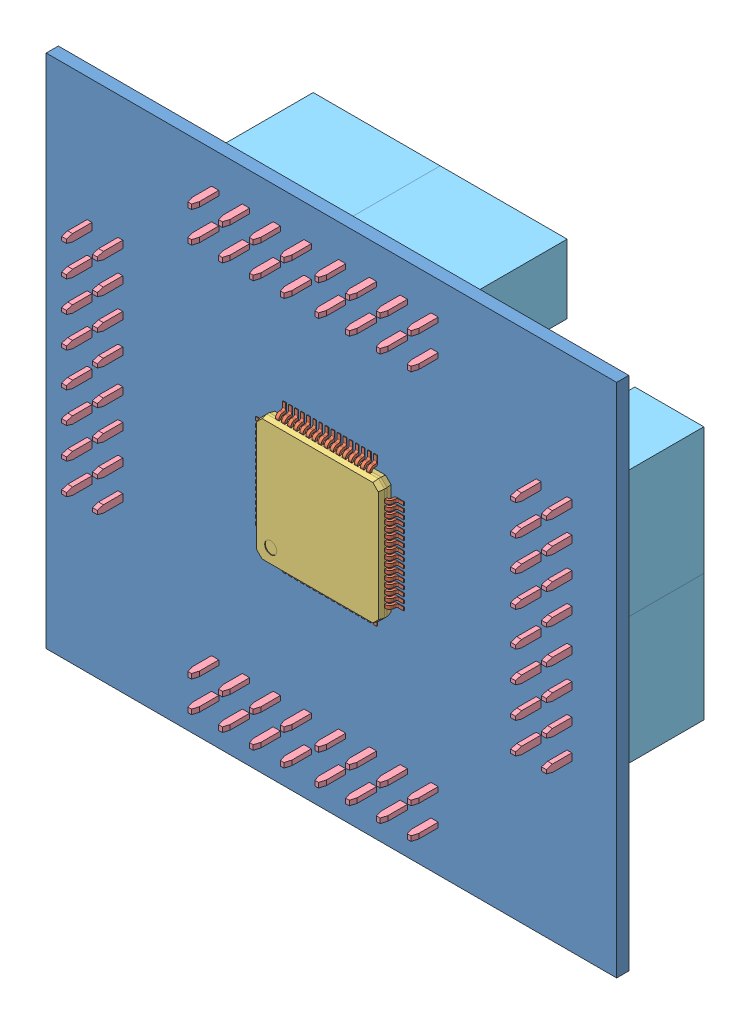
SolidWorks assembly Pic32Board, configuration Défaut. Lengths in mm.
Overall size (47 42.5 11.6).
151 component instances, 5 part files, 10 mates.
Components (placement in the parent):
- Pic32Board-1: Pic32Board [Défaut] at (-29.7416 -22.193 46.5) size (47 42.5 1)
- User Library-TQFP64-2-1: User Library-TQFP64-2 [Default] at (-6.3416 -0.843 48.025) x (1 0 0) z (0 -1 0) size (12.2 1.2 12.2)
  - User Library-TQFP64-2_Leg x0-27 y0-575 z1-0-1: User Library-TQFP64-2_Leg x0-27 y0-575 z1-0 [Default] at (-5.1 0 -1.25) x (0 0 1) z (-1 0 0) size (0.27 0.78 1)
  - User Library-TQFP64-2_Leg x0-27 y0-575 z1-0-2: User Library-TQFP64-2_Leg x0-27 y0-575 z1-0 [Default] at (-2.75 0 -5.1001) x (-1 0 0) z (0 0 -1) size (0.27 0.78 1)
  - User Library-TQFP64-2_Leg x0-27 y0-575 z1-0-3: User Library-TQFP64-2_Leg x0-27 y0-575 z1-0 [Default] at (-5.1 0 2.25) x (0 0 1) z (-1 0 0) size (0.27 0.78 1)
  - User Library-TQFP64-2_Leg x0-27 y0-575 z1-0-4: User Library-TQFP64-2_Leg x0-27 y0-575 z1-0 [Default] at (5.1 0 -3.25) x (0 0 -1) z (1 0 0) size (0.27 0.78 1)
  - User Library-TQFP64-2_Leg x0-27 y0-575 z1-0-5: User Library-TQFP64-2_Leg x0-27 y0-575 z1-0 [Default] at (-1.25 0 5.1001) size (0.27 0.78 1)
  - User Library-TQFP64-2_Leg x0-27 y0-575 z1-0-6: User Library-TQFP64-2_Leg x0-27 y0-575 z1-0 [Default] at (2.75 0 5.1001) size (0.27 0.78 1)
  - User Library-TQFP64-2_Leg x0-27 y0-575 z1-0-7: User Library-TQFP64-2_Leg x0-27 y0-575 z1-0 [Default] at (2.25 0 5.1001) size (0.27 0.78 1)
  - User Library-TQFP64-2_Leg x0-27 y0-575 z1-0-8: User Library-TQFP64-2_Leg x0-27 y0-575 z1-0 [Default] at (5.1 0 -0.25) x (0 0 -1) z (1 0 0) size (0.27 0.78 1)
  - User Library-TQFP64-2_Leg x0-27 y0-575 z1-0-9: User Library-TQFP64-2_Leg x0-27 y0-575 z1-0 [Default] at (-5.1 0 -0.75) x (0 0 1) z (-1 0 0) size (0.27 0.78 1)
  - User Library-TQFP64-2_Leg x0-27 y0-575 z1-0-10: User Library-TQFP64-2_Leg x0-27 y0-575 z1-0 [Default] at (2.25 0 -5.1001) x (-1 0 0) z (0 0 -1) size (0.27 0.78 1)
  - User Library-TQFP64-2_Leg x0-27 y0-575 z1-0-11: User Library-TQFP64-2_Leg x0-27 y0-575 z1-0 [Default] at (5.1 0 0.75) x (0 0 -1) z (1 0 0) size (0.27 0.78 1)
  - User Library-TQFP64-2_Leg x0-27 y0-575 z1-0-12: User Library-TQFP64-2_Leg x0-27 y0-575 z1-0 [Default] at (-0.25 0 -5.1001) x (-1 0 0) z (0 0 -1) size (0.27 0.78 1)
  - User Library-TQFP64-2_Leg x0-27 y0-575 z1-0-13: User Library-TQFP64-2_Leg x0-27 y0-575 z1-0 [Default] at (5.1 0 0.25) x (0 0 -1) z (1 0 0) size (0.27 0.78 1)
  - User Library-TQFP64-2_Leg x0-27 y0-575 z1-0-14: User Library-TQFP64-2_Leg x0-27 y0-575 z1-0 [Default] at (1.75 0 5.1001) size (0.27 0.78 1)
  - User Library-TQFP64-2_Leg x0-27 y0-575 z1-0-15: User Library-TQFP64-2_Leg x0-27 y0-575 z1-0 [Default] at (-1.25 0 -5.1001) x (-1 0 0) z (0 0 -1) size (0.27 0.78 1)
  - User Library-TQFP64-2_Leg x0-27 y0-575 z1-0-16: User Library-TQFP64-2_Leg x0-27 y0-575 z1-0 [Default] at (-5.1 0 1.75) x (0 0 1) z (-1 0 0) size (0.27 0.78 1)
  - User Library-TQFP64-2_Leg x0-27 y0-575 z1-0-17: User Library-TQFP64-2_Leg x0-27 y0-575 z1-0 [Default] at (3.25 0 5.1001) size (0.27 0.78 1)
  - User Library-TQFP64-2_Leg x0-27 y0-575 z1-0-18: User Library-TQFP64-2_Leg x0-27 y0-575 z1-0 [Default] at (2.75 0 -5.1001) x (-1 0 0) z (0 0 -1) size (0.27 0.78 1)
  - User Library-TQFP64-2_Leg x0-27 y0-575 z1-0-19: User Library-TQFP64-2_Leg x0-27 y0-575 z1-0 [Default] at (5.1 0 2.25) x (0 0 -1) z (1 0 0) size (0.27 0.78 1)
  - User Library-TQFP64-2_Leg x0-27 y0-575 z1-0-20: User Library-TQFP64-2_Leg x0-27 y0-575 z1-0 [Default] at (-3.25 0 -5.1001) x (-1 0 0) z (0 0 -1) size (0.27 0.78 1)
  - User Library-TQFP64-2_Leg x0-27 y0-575 z1-0-21: User Library-TQFP64-2_Leg x0-27 y0-575 z1-0 [Default] at (-3.75 0 5.1001) size (0.27 0.78 1)
  - User Library-TQFP64-2_Leg x0-27 y0-575 z1-0-22: User Library-TQFP64-2_Leg x0-27 y0-575 z1-0 [Default] at (-3.25 0 5.1001) size (0.27 0.78 1)
  - User Library-TQFP64-2_Leg x0-27 y0-575 z1-0-23: User Library-TQFP64-2_Leg x0-27 y0-575 z1-0 [Default] at (3.75 0 5.1001) size (0.27 0.78 1)
  - User Library-TQFP64-2_Leg x0-27 y0-575 z1-0-24: User Library-TQFP64-2_Leg x0-27 y0-575 z1-0 [Default] at (-5.1 0 0.25) x (0 0 1) z (-1 0 0) size (0.27 0.78 1)
  - User Library-TQFP64-2_Leg x0-27 y0-575 z1-0-25: User Library-TQFP64-2_Leg x0-27 y0-575 z1-0 [Default] at (5.1 0 3.25) x (0 0 -1) z (1 0 0) size (0.27 0.78 1)
  - User Library-TQFP64-2_Leg x0-27 y0-575 z1-0-26: User Library-TQFP64-2_Leg x0-27 y0-575 z1-0 [Default] at (-5.1 0 0.75) x (0 0 1) z (-1 0 0) size (0.27 0.78 1)
  - User Library-TQFP64-2_Leg x0-27 y0-575 z1-0-27: User Library-TQFP64-2_Leg x0-27 y0-575 z1-0 [Default] at (0.75 0 -5.1001) x (-1 0 0) z (0 0 -1) size (0.27 0.78 1)
  - User Library-TQFP64-2_Leg x0-27 y0-575 z1-0-28: User Library-TQFP64-2_Leg x0-27 y0-575 z1-0 [Default] at (5.1 0 1.75) x (0 0 -1) z (1 0 0) size (0.27 0.78 1)
  - User Library-TQFP64-2_Leg x0-27 y0-575 z1-0-29: User Library-TQFP64-2_Leg x0-27 y0-575 z1-0 [Default] at (-5.1 0 -3.75) x (0 0 1) z (-1 0 0) size (0.27 0.78 1)
  - User Library-TQFP64-2_Leg x0-27 y0-575 z1-0-30: User Library-TQFP64-2_Leg x0-27 y0-575 z1-0 [Default] at (5.1 0 -0.75) x (0 0 -1) z (1 0 0) size (0.27 0.78 1)
  - User Library-TQFP64-2_Leg x0-27 y0-575 z1-0-31: User Library-TQFP64-2_Leg x0-27 y0-575 z1-0 [Default] at (5.1 0 3.75) x (0 0 -1) z (1 0 0) size (0.27 0.78 1)
  - User Library-TQFP64-2_Leg x0-27 y0-575 z1-0-32: User Library-TQFP64-2_Leg x0-27 y0-575 z1-0 [Default] at (-2.25 0 5.1001) size (0.27 0.78 1)
  - User Library-TQFP64-2_Leg x0-27 y0-575 z1-0-33: User Library-TQFP64-2_Leg x0-27 y0-575 z1-0 [Default] at (-5.1 0 -3.25) x (0 0 1) z (-1 0 0) size (0.27 0.78 1)
  - User Library-TQFP64-2_Leg x0-27 y0-575 z1-0-34: User Library-TQFP64-2_Leg x0-27 y0-575 z1-0 [Default] at (-5.1 0 2.75) x (0 0 1) z (-1 0 0) size (0.27 0.78 1)
  - User Library-TQFP64-2_Leg x0-27 y0-575 z1-0-35: User Library-TQFP64-2_Leg x0-27 y0-575 z1-0 [Default] at (-5.1 0 3.75) x (0 0 1) z (-1 0 0) size (0.27 0.78 1)
  - User Library-TQFP64-2_Leg x0-27 y0-575 z1-0-36: User Library-TQFP64-2_Leg x0-27 y0-575 z1-0 [Default] at (1.25 0 -5.1001) x (-1 0 0) z (0 0 -1) size (0.27 0.78 1)
  - User Library-TQFP64-2_Leg x0-27 y0-575 z1-0-37: User Library-TQFP64-2_Leg x0-27 y0-575 z1-0 [Default] at (1.25 0 5.1001) size (0.27 0.78 1)
  - User Library-TQFP64-2_Leg x0-27 y0-575 z1-0-38: User Library-TQFP64-2_Leg x0-27 y0-575 z1-0 [Default] at (5.1 0 1.25) x (0 0 -1) z (1 0 0) size (0.27 0.78 1)
  - User Library-TQFP64-2_Leg x0-27 y0-575 z1-0-39: User Library-TQFP64-2_Leg x0-27 y0-575 z1-0 [Default] at (0.75 0 5.1001) size (0.27 0.78 1)
  - User Library-TQFP64-2_Leg x0-27 y0-575 z1-0-40: User Library-TQFP64-2_Leg x0-27 y0-575 z1-0 [Default] at (3.25 0 -5.1001) x (-1 0 0) z (0 0 -1) size (0.27 0.78 1)
  - User Library-TQFP64-2_Leg x0-27 y0-575 z1-0-41: User Library-TQFP64-2_Leg x0-27 y0-575 z1-0 [Default] at (-2.75 0 5.1001) size (0.27 0.78 1)
  - User Library-TQFP64-2_Leg x0-27 y0-575 z1-0-42: User Library-TQFP64-2_Leg x0-27 y0-575 z1-0 [Default] at (3.75 0 -5.1001) x (-1 0 0) z (0 0 -1) size (0.27 0.78 1)
  - User Library-TQFP64-2_Leg x0-27 y0-575 z1-0-43: User Library-TQFP64-2_Leg x0-27 y0-575 z1-0 [Default] at (1.75 0 -5.1001) x (-1 0 0) z (0 0 -1) size (0.27 0.78 1)
  - User Library-TQFP64-2_Leg x0-27 y0-575 z1-0-44: User Library-TQFP64-2_Leg x0-27 y0-575 z1-0 [Default] at (-5.1 0 -2.75) x (0 0 1) z (-1 0 0) size (0.27 0.78 1)
  - User Library-TQFP64-2_Leg x0-27 y0-575 z1-0-45: User Library-TQFP64-2_Leg x0-27 y0-575 z1-0 [Default] at (5.1 0 -2.25) x (0 0 -1) z (1 0 0) size (0.27 0.78 1)
  - User Library-TQFP64-2_Leg x0-27 y0-575 z1-0-46: User Library-TQFP64-2_Leg x0-27 y0-575 z1-0 [Default] at (-2.25 0 -5.1001) x (-1 0 0) z (0 0 -1) size (0.27 0.78 1)
  - User Library-TQFP64-2_Leg x0-27 y0-575 z1-0-47: User Library-TQFP64-2_Leg x0-27 y0-575 z1-0 [Default] at (-5.1 0 1.25) x (0 0 1) z (-1 0 0) size (0.27 0.78 1)
  - User Library-TQFP64-2_Leg x0-27 y0-575 z1-0-48: User Library-TQFP64-2_Leg x0-27 y0-575 z1-0 [Default] at (5.1 0 -3.75) x (0 0 -1) z (1 0 0) size (0.27 0.78 1)
  - User Library-TQFP64-2_Leg x0-27 y0-575 z1-0-49: User Library-TQFP64-2_Leg x0-27 y0-575 z1-0 [Default] at (0.25 0 -5.1001) x (-1 0 0) z (0 0 -1) size (0.27 0.78 1)
  - User Library-TQFP64-2_Leg x0-27 y0-575 z1-0-50: User Library-TQFP64-2_Leg x0-27 y0-575 z1-0 [Default] at (-3.75 0 -5.1001) x (-1 0 0) z (0 0 -1) size (0.27 0.78 1)
  - User Library-TQFP64-2_Leg x0-27 y0-575 z1-0-51: User Library-TQFP64-2_Leg x0-27 y0-575 z1-0 [Default] at (-5.1 0 -0.25) x (0 0 1) z (-1 0 0) size (0.27 0.78 1)
  - User Library-TQFP64-2_Leg x0-27 y0-575 z1-0-52: User Library-TQFP64-2_Leg x0-27 y0-575 z1-0 [Default] at (-0.75 0 5.1001) size (0.27 0.78 1)
  - User Library-TQFP64-2_Leg x0-27 y0-575 z1-0-53: User Library-TQFP64-2_Leg x0-27 y0-575 z1-0 [Default] at (5.1 0 -1.75) x (0 0 -1) z (1 0 0) size (0.27 0.78 1)
  - User Library-TQFP64-2_Leg x0-27 y0-575 z1-0-54: User Library-TQFP64-2_Leg x0-27 y0-575 z1-0 [Default] at (-5.1 0 -2.25) x (0 0 1) z (-1 0 0) size (0.27 0.78 1)
  - User Library-TQFP64-2_Leg x0-27 y0-575 z1-0-55: User Library-TQFP64-2_Leg x0-27 y0-575 z1-0 [Default] at (-0.75 0 -5.1001) x (-1 0 0) z (0 0 -1) size (0.27 0.78 1)
  - User Library-TQFP64-2_Leg x0-27 y0-575 z1-0-56: User Library-TQFP64-2_Leg x0-27 y0-575 z1-0 [Default] at (-5.1 0 3.25) x (0 0 1) z (-1 0 0) size (0.27 0.78 1)
  - User Library-TQFP64-2_Body x10-2 y10-2 z1-05-1: User Library-TQFP64-2_Body x10-2 y10-2 z1-05 [Default] at origin size (10.2 1.05 10.2)
  - User Library-TQFP64-2_Leg x0-27 y0-575 z1-0-57: User Library-TQFP64-2_Leg x0-27 y0-575 z1-0 [Default] at (0.25 0 5.1001) size (0.27 0.78 1)
  - User Library-TQFP64-2_Leg x0-27 y0-575 z1-0-58: User Library-TQFP64-2_Leg x0-27 y0-575 z1-0 [Default] at (5.1 0 2.75) x (0 0 -1) z (1 0 0) size (0.27 0.78 1)
  - User Library-TQFP64-2_Leg x0-27 y0-575 z1-0-59: User Library-TQFP64-2_Leg x0-27 y0-575 z1-0 [Default] at (-1.75 0 -5.1001) x (-1 0 0) z (0 0 -1) size (0.27 0.78 1)
  - User Library-TQFP64-2_Leg x0-27 y0-575 z1-0-60: User Library-TQFP64-2_Leg x0-27 y0-575 z1-0 [Default] at (-5.1 0 -1.75) x (0 0 1) z (-1 0 0) size (0.27 0.78 1)
  - User Library-TQFP64-2_Leg x0-27 y0-575 z1-0-61: User Library-TQFP64-2_Leg x0-27 y0-575 z1-0 [Default] at (-0.25 0 5.1001) size (0.27 0.78 1)
  - User Library-TQFP64-2_Leg x0-27 y0-575 z1-0-62: User Library-TQFP64-2_Leg x0-27 y0-575 z1-0 [Default] at (-1.75 0 5.1001) size (0.27 0.78 1)
  - User Library-TQFP64-2_Leg x0-27 y0-575 z1-0-63: User Library-TQFP64-2_Leg x0-27 y0-575 z1-0 [Default] at (5.1 0 -2.75) x (0 0 -1) z (1 0 0) size (0.27 0.78 1)
  - User Library-TQFP64-2_Leg x0-27 y0-575 z1-0-64: User Library-TQFP64-2_Leg x0-27 y0-575 z1-0 [Default] at (5.1 0 -1.25) x (0 0 -1) z (1 0 0) size (0.27 0.78 1)
- HE10-16Way-Female-1: HE10-16Way-Female [Défaut] at (-8.4334 -17.4128 55.4002) x (1 0 0) z (0 0 -1) size (20.92 5.68 11.6)
  - User Library-MULTICOMP 2214S-08SG-85-1: User Library-MULTICOMP 2214S-08SG-85 [Default] at (-3.5782 -0.0598 8.9002) size (10.46 5.68 11.6)
    - User Library-MULTICOMP 2214S-08SG-85_contact-1: User Library-MULTICOMP 2214S-08SG-85_contact [Default] at (-3.81 -1.07 0.9) x (1 0 0) z (0 -1 0) size (2 10 0.4)
    - User Library-MULTICOMP 2214S-08SG-85_contact-2: User Library-MULTICOMP 2214S-08SG-85_contact [Default] at (-3.81 1.47 0.9) x (1 0 0) z (0 -1 0) size (2 10 0.4)
    - User Library-MULTICOMP 2214S-08SG-85_contact-3: User Library-MULTICOMP 2214S-08SG-85_contact [Default] at (-1.27 -1.07 0.9) x (1 0 0) z (0 -1 0) size (2 10 0.4)
    - User Library-MULTICOMP 2214S-08SG-85_contact-4: User Library-MULTICOMP 2214S-08SG-85_contact [Default] at (-1.27 1.47 0.9) x (1 0 0) z (0 -1 0) size (2 10 0.4)
    - User Library-MULTICOMP 2214S-08SG-85_contact-5: User Library-MULTICOMP 2214S-08SG-85_contact [Default] at (1.27 1.47 0.9) x (1 0 0) z (0 -1 0) size (2 10 0.4)
    - User Library-MULTICOMP 2214S-08SG-85_contact-6: User Library-MULTICOMP 2214S-08SG-85_contact [Default] at (1.27 -1.07 0.9) x (1 0 0) z (0 -1 0) size (2 10 0.4)
    - User Library-MULTICOMP 2214S-08SG-85_contact-7: User Library-MULTICOMP 2214S-08SG-85_contact [Default] at (3.81 -1.47 0.9) x (-1 0 0) z (0 1 0) size (2 10 0.4)
    - User Library-MULTICOMP 2214S-08SG-85_contact-8: User Library-MULTICOMP 2214S-08SG-85_contact [Default] at (3.81 1.07 0.9) x (-1 0 0) z (0 1 0) size (2 10 0.4)
    - User Library-MULTICOMP 2214S-08SG-85_housing-1: User Library-MULTICOMP 2214S-08SG-85_housing [Default] at origin size (10.46 5.68 8.5)
  - User Library-MULTICOMP 2214S-08SG-85-2: User Library-MULTICOMP 2214S-08SG-85 [Default] at (6.8818 -0.0598 8.9002) size (10.46 5.68 11.6)
    - User Library-MULTICOMP 2214S-08SG-85_contact-1: User Library-MULTICOMP 2214S-08SG-85_contact [Default] at (-3.81 -1.07 0.9) x (1 0 0) z (0 -1 0) size (2 10 0.4)
    - User Library-MULTICOMP 2214S-08SG-85_contact-2: User Library-MULTICOMP 2214S-08SG-85_contact [Default] at (-3.81 1.47 0.9) x (1 0 0) z (0 -1 0) size (2 10 0.4)
    - User Library-MULTICOMP 2214S-08SG-85_contact-3: User Library-MULTICOMP 2214S-08SG-85_contact [Default] at (-1.27 -1.07 0.9) x (1 0 0) z (0 -1 0) size (2 10 0.4)
    - User Library-MULTICOMP 2214S-08SG-85_contact-4: User Library-MULTICOMP 2214S-08SG-85_contact [Default] at (-1.27 1.47 0.9) x (1 0 0) z (0 -1 0) size (2 10 0.4)
    - User Library-MULTICOMP 2214S-08SG-85_contact-5: User Library-MULTICOMP 2214S-08SG-85_contact [Default] at (1.27 1.47 0.9) x (1 0 0) z (0 -1 0) size (2 10 0.4)
    - User Library-MULTICOMP 2214S-08SG-85_contact-6: User Library-MULTICOMP 2214S-08SG-85_contact [Default] at (1.27 -1.07 0.9) x (1 0 0) z (0 -1 0) size (2 10 0.4)
    - User Library-MULTICOMP 2214S-08SG-85_contact-7: User Library-MULTICOMP 2214S-08SG-85_contact [Default] at (3.81 -1.47 0.9) x (-1 0 0) z (0 1 0) size (2 10 0.4)
    - User Library-MULTICOMP 2214S-08SG-85_contact-8: User Library-MULTICOMP 2214S-08SG-85_contact [Default] at (3.81 1.07 0.9) x (-1 0 0) z (0 1 0) size (2 10 0.4)
    - User Library-MULTICOMP 2214S-08SG-85_housing-1: User Library-MULTICOMP 2214S-08SG-85_housing [Default] at origin size (10.46 5.68 8.5)
- HE10-16Way-Female-2: HE10-16Way-Female [Défaut] at (-8.4334 16.0872 55.4002) x (1 0 0) z (0 0 -1) size (20.92 5.68 11.6)
  - User Library-MULTICOMP 2214S-08SG-85-1: User Library-MULTICOMP 2214S-08SG-85 [Default] at (-3.5782 -0.0598 8.9002) size (10.46 5.68 11.6)
    - User Library-MULTICOMP 2214S-08SG-85_contact-1: User Library-MULTICOMP 2214S-08SG-85_contact [Default] at (-3.81 -1.07 0.9) x (1 0 0) z (0 -1 0) size (2 10 0.4)
    - User Library-MULTICOMP 2214S-08SG-85_contact-2: User Library-MULTICOMP 2214S-08SG-85_contact [Default] at (-3.81 1.47 0.9) x (1 0 0) z (0 -1 0) size (2 10 0.4)
    - User Library-MULTICOMP 2214S-08SG-85_contact-3: User Library-MULTICOMP 2214S-08SG-85_contact [Default] at (-1.27 -1.07 0.9) x (1 0 0) z (0 -1 0) size (2 10 0.4)
    - User Library-MULTICOMP 2214S-08SG-85_contact-4: User Library-MULTICOMP 2214S-08SG-85_contact [Default] at (-1.27 1.47 0.9) x (1 0 0) z (0 -1 0) size (2 10 0.4)
    - User Library-MULTICOMP 2214S-08SG-85_contact-5: User Library-MULTICOMP 2214S-08SG-85_contact [Default] at (1.27 1.47 0.9) x (1 0 0) z (0 -1 0) size (2 10 0.4)
    - User Library-MULTICOMP 2214S-08SG-85_contact-6: User Library-MULTICOMP 2214S-08SG-85_contact [Default] at (1.27 -1.07 0.9) x (1 0 0) z (0 -1 0) size (2 10 0.4)
    - User Library-MULTICOMP 2214S-08SG-85_contact-7: User Library-MULTICOMP 2214S-08SG-85_contact [Default] at (3.81 -1.47 0.9) x (-1 0 0) z (0 1 0) size (2 10 0.4)
    - User Library-MULTICOMP 2214S-08SG-85_contact-8: User Library-MULTICOMP 2214S-08SG-85_contact [Default] at (3.81 1.07 0.9) x (-1 0 0) z (0 1 0) size (2 10 0.4)
    - User Library-MULTICOMP 2214S-08SG-85_housing-1: User Library-MULTICOMP 2214S-08SG-85_housing [Default] at origin size (10.46 5.68 8.5)
  - User Library-MULTICOMP 2214S-08SG-85-2: User Library-MULTICOMP 2214S-08SG-85 [Default] at (6.8818 -0.0598 8.9002) size (10.46 5.68 11.6)
    - User Library-MULTICOMP 2214S-08SG-85_contact-1: User Library-MULTICOMP 2214S-08SG-85_contact [Default] at (-3.81 -1.07 0.9) x (1 0 0) z (0 -1 0) size (2 10 0.4)
    - User Library-MULTICOMP 2214S-08SG-85_contact-2: User Library-MULTICOMP 2214S-08SG-85_contact [Default] at (-3.81 1.47 0.9) x (1 0 0) z (0 -1 0) size (2 10 0.4)
    - User Library-MULTICOMP 2214S-08SG-85_contact-3: User Library-MULTICOMP 2214S-08SG-85_contact [Default] at (-1.27 -1.07 0.9) x (1 0 0) z (0 -1 0) size (2 10 0.4)
    - User Library-MULTICOMP 2214S-08SG-85_contact-4: User Library-MULTICOMP 2214S-08SG-85_contact [Default] at (-1.27 1.47 0.9) x (1 0 0) z (0 -1 0) size (2 10 0.4)
    - User Library-MULTICOMP 2214S-08SG-85_contact-5: User Library-MULTICOMP 2214S-08SG-85_contact [Default] at (1.27 1.47 0.9) x (1 0 0) z (0 -1 0) size (2 10 0.4)
    - User Library-MULTICOMP 2214S-08SG-85_contact-6: User Library-MULTICOMP 2214S-08SG-85_contact [Default] at (1.27 -1.07 0.9) x (1 0 0) z (0 -1 0) size (2 10 0.4)
    - User Library-MULTICOMP 2214S-08SG-85_contact-7: User Library-MULTICOMP 2214S-08SG-85_contact [Default] at (3.81 -1.47 0.9) x (-1 0 0) z (0 1 0) size (2 10 0.4)
    - User Library-MULTICOMP 2214S-08SG-85_contact-8: User Library-MULTICOMP 2214S-08SG-85_contact [Default] at (3.81 1.07 0.9) x (-1 0 0) z (0 1 0) size (2 10 0.4)
    - User Library-MULTICOMP 2214S-08SG-85_housing-1: User Library-MULTICOMP 2214S-08SG-85_housing [Default] at origin size (10.46 5.68 8.5)
- HE10-16Way-Female-3: HE10-16Way-Female [Défaut] at (-24.9614 2.4188 55.4002) x (0 -1 0) z (0 0 -1) size (20.92 5.68 11.6)
  - User Library-MULTICOMP 2214S-08SG-85-1: User Library-MULTICOMP 2214S-08SG-85 [Default] at (-3.5782 -0.0598 8.9002) size (10.46 5.68 11.6)
    - User Library-MULTICOMP 2214S-08SG-85_contact-1: User Library-MULTICOMP 2214S-08SG-85_contact [Default] at (-3.81 -1.07 0.9) x (1 0 0) z (0 -1 0) size (2 10 0.4)
    - User Library-MULTICOMP 2214S-08SG-85_contact-2: User Library-MULTICOMP 2214S-08SG-85_contact [Default] at (-3.81 1.47 0.9) x (1 0 0) z (0 -1 0) size (2 10 0.4)
    - User Library-MULTICOMP 2214S-08SG-85_contact-3: User Library-MULTICOMP 2214S-08SG-85_contact [Default] at (-1.27 -1.07 0.9) x (1 0 0) z (0 -1 0) size (2 10 0.4)
    - User Library-MULTICOMP 2214S-08SG-85_contact-4: User Library-MULTICOMP 2214S-08SG-85_contact [Default] at (-1.27 1.47 0.9) x (1 0 0) z (0 -1 0) size (2 10 0.4)
    - User Library-MULTICOMP 2214S-08SG-85_contact-5: User Library-MULTICOMP 2214S-08SG-85_contact [Default] at (1.27 1.47 0.9) x (1 0 0) z (0 -1 0) size (2 10 0.4)
    - User Library-MULTICOMP 2214S-08SG-85_contact-6: User Library-MULTICOMP 2214S-08SG-85_contact [Default] at (1.27 -1.07 0.9) x (1 0 0) z (0 -1 0) size (2 10 0.4)
    - User Library-MULTICOMP 2214S-08SG-85_contact-7: User Library-MULTICOMP 2214S-08SG-85_contact [Default] at (3.81 -1.47 0.9) x (-1 0 0) z (0 1 0) size (2 10 0.4)
    - User Library-MULTICOMP 2214S-08SG-85_contact-8: User Library-MULTICOMP 2214S-08SG-85_contact [Default] at (3.81 1.07 0.9) x (-1 0 0) z (0 1 0) size (2 10 0.4)
    - User Library-MULTICOMP 2214S-08SG-85_housing-1: User Library-MULTICOMP 2214S-08SG-85_housing [Default] at origin size (10.46 5.68 8.5)
  - User Library-MULTICOMP 2214S-08SG-85-2: User Library-MULTICOMP 2214S-08SG-85 [Default] at (6.8818 -0.0598 8.9002) size (10.46 5.68 11.6)
    - User Library-MULTICOMP 2214S-08SG-85_contact-1: User Library-MULTICOMP 2214S-08SG-85_contact [Default] at (-3.81 -1.07 0.9) x (1 0 0) z (0 -1 0) size (2 10 0.4)
    - User Library-MULTICOMP 2214S-08SG-85_contact-2: User Library-MULTICOMP 2214S-08SG-85_contact [Default] at (-3.81 1.47 0.9) x (1 0 0) z (0 -1 0) size (2 10 0.4)
    - User Library-MULTICOMP 2214S-08SG-85_contact-3: User Library-MULTICOMP 2214S-08SG-85_contact [Default] at (-1.27 -1.07 0.9) x (1 0 0) z (0 -1 0) size (2 10 0.4)
    - User Library-MULTICOMP 2214S-08SG-85_contact-4: User Library-MULTICOMP 2214S-08SG-85_contact [Default] at (-1.27 1.47 0.9) x (1 0 0) z (0 -1 0) size (2 10 0.4)
    - User Library-MULTICOMP 2214S-08SG-85_contact-5: User Library-MULTICOMP 2214S-08SG-85_contact [Default] at (1.27 1.47 0.9) x (1 0 0) z (0 -1 0) size (2 10 0.4)
    - User Library-MULTICOMP 2214S-08SG-85_contact-6: User Library-MULTICOMP 2214S-08SG-85_contact [Default] at (1.27 -1.07 0.9) x (1 0 0) z (0 -1 0) size (2 10 0.4)
    - User Library-MULTICOMP 2214S-08SG-85_contact-7: User Library-MULTICOMP 2214S-08SG-85_contact [Default] at (3.81 -1.47 0.9) x (-1 0 0) z (0 1 0) size (2 10 0.4)
    - User Library-MULTICOMP 2214S-08SG-85_contact-8: User Library-MULTICOMP 2214S-08SG-85_contact [Default] at (3.81 1.07 0.9) x (-1 0 0) z (0 1 0) size (2 10 0.4)
    - User Library-MULTICOMP 2214S-08SG-85_housing-1: User Library-MULTICOMP 2214S-08SG-85_housing [Default] at origin size (10.46 5.68 8.5)
- HE10-16Way-Female-4: HE10-16Way-Female [Défaut] at (12.0386 2.4188 55.4002) x (0 -1 0) z (0 0 -1) size (20.92 5.68 11.6)
  - User Library-MULTICOMP 2214S-08SG-85-1: User Library-MULTICOMP 2214S-08SG-85 [Default] at (-3.5782 -0.0598 8.9002) size (10.46 5.68 11.6)
    - User Library-MULTICOMP 2214S-08SG-85_contact-1: User Library-MULTICOMP 2214S-08SG-85_contact [Default] at (-3.81 -1.07 0.9) x (1 0 0) z (0 -1 0) size (2 10 0.4)
    - User Library-MULTICOMP 2214S-08SG-85_contact-2: User Library-MULTICOMP 2214S-08SG-85_contact [Default] at (-3.81 1.47 0.9) x (1 0 0) z (0 -1 0) size (2 10 0.4)
    - User Library-MULTICOMP 2214S-08SG-85_contact-3: User Library-MULTICOMP 2214S-08SG-85_contact [Default] at (-1.27 -1.07 0.9) x (1 0 0) z (0 -1 0) size (2 10 0.4)
    - User Library-MULTICOMP 2214S-08SG-85_contact-4: User Library-MULTICOMP 2214S-08SG-85_contact [Default] at (-1.27 1.47 0.9) x (1 0 0) z (0 -1 0) size (2 10 0.4)
    - User Library-MULTICOMP 2214S-08SG-85_contact-5: User Library-MULTICOMP 2214S-08SG-85_contact [Default] at (1.27 1.47 0.9) x (1 0 0) z (0 -1 0) size (2 10 0.4)
    - User Library-MULTICOMP 2214S-08SG-85_contact-6: User Library-MULTICOMP 2214S-08SG-85_contact [Default] at (1.27 -1.07 0.9) x (1 0 0) z (0 -1 0) size (2 10 0.4)
    - User Library-MULTICOMP 2214S-08SG-85_contact-7: User Library-MULTICOMP 2214S-08SG-85_contact [Default] at (3.81 -1.47 0.9) x (-1 0 0) z (0 1 0) size (2 10 0.4)
    - User Library-MULTICOMP 2214S-08SG-85_contact-8: User Library-MULTICOMP 2214S-08SG-85_contact [Default] at (3.81 1.07 0.9) x (-1 0 0) z (0 1 0) size (2 10 0.4)
    - User Library-MULTICOMP 2214S-08SG-85_housing-1: User Library-MULTICOMP 2214S-08SG-85_housing [Default] at origin size (10.46 5.68 8.5)
  - User Library-MULTICOMP 2214S-08SG-85-2: User Library-MULTICOMP 2214S-08SG-85 [Default] at (6.8818 -0.0598 8.9002) size (10.46 5.68 11.6)
    - User Library-MULTICOMP 2214S-08SG-85_contact-1: User Library-MULTICOMP 2214S-08SG-85_contact [Default] at (-3.81 -1.07 0.9) x (1 0 0) z (0 -1 0) size (2 10 0.4)
    - User Library-MULTICOMP 2214S-08SG-85_contact-2: User Library-MULTICOMP 2214S-08SG-85_contact [Default] at (-3.81 1.47 0.9) x (1 0 0) z (0 -1 0) size (2 10 0.4)
    - User Library-MULTICOMP 2214S-08SG-85_contact-3: User Library-MULTICOMP 2214S-08SG-85_contact [Default] at (-1.27 -1.07 0.9) x (1 0 0) z (0 -1 0) size (2 10 0.4)
    - User Library-MULTICOMP 2214S-08SG-85_contact-4: User Library-MULTICOMP 2214S-08SG-85_contact [Default] at (-1.27 1.47 0.9) x (1 0 0) z (0 -1 0) size (2 10 0.4)
    - User Library-MULTICOMP 2214S-08SG-85_contact-5: User Library-MULTICOMP 2214S-08SG-85_contact [Default] at (1.27 1.47 0.9) x (1 0 0) z (0 -1 0) size (2 10 0.4)
    - User Library-MULTICOMP 2214S-08SG-85_contact-6: User Library-MULTICOMP 2214S-08SG-85_contact [Default] at (1.27 -1.07 0.9) x (1 0 0) z (0 -1 0) size (2 10 0.4)
    - User Library-MULTICOMP 2214S-08SG-85_contact-7: User Library-MULTICOMP 2214S-08SG-85_contact [Default] at (3.81 -1.47 0.9) x (-1 0 0) z (0 1 0) size (2 10 0.4)
    - User Library-MULTICOMP 2214S-08SG-85_contact-8: User Library-MULTICOMP 2214S-08SG-85_contact [Default] at (3.81 1.07 0.9) x (-1 0 0) z (0 1 0) size (2 10 0.4)
    - User Library-MULTICOMP 2214S-08SG-85_housing-1: User Library-MULTICOMP 2214S-08SG-85_housing [Default] at origin size (10.46 5.68 8.5)
Mates (geometry in assembly coordinates):
- Coïncidente1: coincident anti-aligned: plane of Pic32Board-1 through (-29.7416 -22.193 47.5) normal (0 0 1); plane of ? through (-6.3763 1.763 47.5) normal (0 0 -1)
- Coïncidente2: coincident anti-aligned: plane of Pic32Board-1 through (-29.7416 -22.193 47.5) normal (0 0 1); plane of User Library-TQFP64-2-1/User Library-TQFP64-2_Body x10-2 y10-2 z1-05-1 through (-1.2416 4.257 47.5) normal (0 0 -1)
- Distance3: distance = 18.5 mm: line of User Library-TQFP64-2-1/User Library-TQFP64-2_Body x10-2 y10-2 z1-05-1 through (-1.2416 -5.443 48.125) axis (0 1 0); plane of Pic32Board-1 through (17.2584 -22.193 47.5) normal (1 0 0)
- Distance4: distance = 16.25 mm: line of User Library-TQFP64-2-1/User Library-TQFP64-2_Body x10-2 y10-2 z1-05-1 through (-10.9416 -5.943 48.125) axis (1 0 0); plane of Pic32Board-1 through (-29.7416 -22.193 47.5) normal (0 -1 0)
- Coïncidente3: coincident anti-aligned: plane of Pic32Board-1 through (-29.7416 -22.193 46.5) normal (0 0 -1); plane of HE10-16Way-Female-1/User Library-MULTICOMP 2214S-08SG-85-2/User Library-MULTICOMP 2214S-08SG-85_housing-1 through (-1.5516 -17.353 46.5) normal (0 0 1)
- Distance5: distance = 2 mm aligned: plane of Pic32Board-1 through (-29.7416 -22.193 47.5) normal (0 -1 0); plane of HE10-16Way-Female-1/User Library-MULTICOMP 2214S-08SG-85-2/User Library-MULTICOMP 2214S-08SG-85_housing-1 through (-1.5516 -20.193 46.5) normal (0 -1 0)
- Distance6: distance = 12.5 mm aligned: plane of Pic32Board-1 through (-29.7416 -22.193 47.5) normal (-1 0 0); plane of HE10-16Way-Female-1/User Library-MULTICOMP 2214S-08SG-85-1/User Library-MULTICOMP 2214S-08SG-85_housing-1 through (-17.2416 -20.193 46.5) normal (-1 0 0)
- Distance7: distance = 2 mm aligned: plane of HE10-16Way-Female-3/User Library-MULTICOMP 2214S-08SG-85-2/User Library-MULTICOMP 2214S-08SG-85_housing-1 through (-27.7416 -4.463 46.5) normal (-1 0 0); plane of Pic32Board-1 through (-29.7416 -22.193 47.5) normal (-1 0 0)
- Coïncidente7: coincident anti-aligned: plane of Pic32Board-1 through (-29.7416 -22.193 46.5) normal (0 0 -1); plane of HE10-16Way-Female-3/User Library-MULTICOMP 2214S-08SG-85-2/User Library-MULTICOMP 2214S-08SG-85_housing-1 through (-24.9016 -4.463 46.5) normal (0 0 1)
- Distance8: distance = 12.5 mm aligned: plane of Pic32Board-1 through (-29.7416 -22.193 47.5) normal (0 -1 0); plane of HE10-16Way-Female-3/User Library-MULTICOMP 2214S-08SG-85-2/User Library-MULTICOMP 2214S-08SG-85_housing-1 through (-22.0616 -9.693 46.5) normal (0 -1 0)
